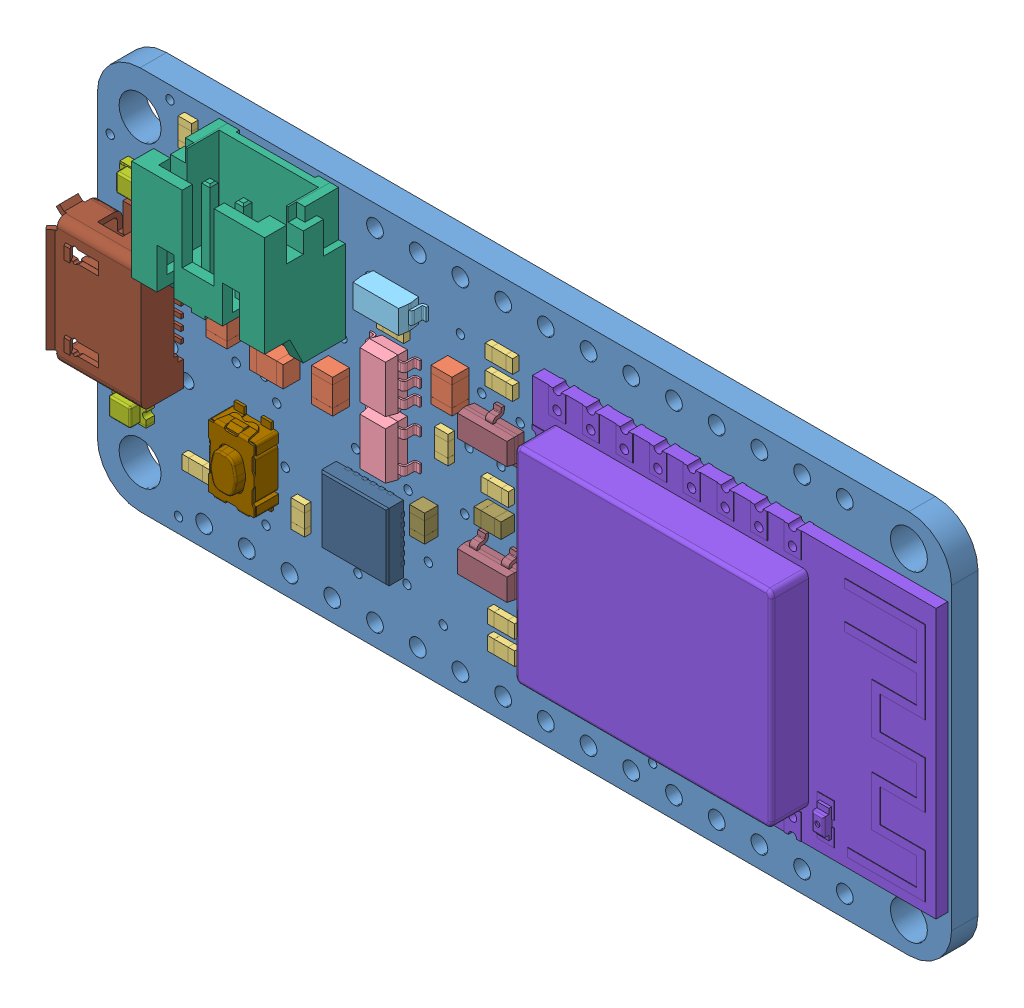
SolidWorks assembly 2821 Adafruit ESP8266 Feather, configuration Default. Lengths in mm.
Overall size (51.25 22.86 6.37).
31 component instances, 13 part files, 0 mates.
Components (placement in the parent):
- 2821 Adafruit ESP8266 Feather(2)^2821 Adafruit ESP8266 Feather-1: 2821 Adafruit ESP8266 Feather(2)^2821 Adafruit ESP8266 Feather [Default] at origin size (51.25 22.86 6.37) (virtual)
  - PCB Component^2821 Adafruit ESP8266 Feather(2)_2821 Adafruit ESP8266 Feather-1: PCB Component^2821 Adafruit ESP8266 Feather(2)_2821 Adafruit ESP8266 Feather [Default] at origin size (51.25 22.86 6.37) (virtual)
    - Board^PCB Component_2821 Adafruit ESP8266 Feather(2)_2821 Adafruit ESP8266 Feather-1: Board^PCB Component_2821 Adafruit ESP8266 Feather(2)_2821 Adafruit ESP8266 Feather [Default] at origin size (50.8 22.86 1.57) (virtual)
    - 10uF^PCB Component_2821 Adafruit ESP8266 Feather(2)_2821 Adafruit ESP8266 Feather-1: 10uF^PCB Component_2821 Adafruit ESP8266 Feather(2)_2821 Adafruit ESP8266 Feather [Default] at (8.088 12.959 1.57) x (0 1 0) z (0 0 1) size (2 1.25 1) (virtual)
    - 10uF^PCB Component_2821 Adafruit ESP8266 Feather(2)_2821 Adafruit ESP8266 Feather-2: 10uF^PCB Component_2821 Adafruit ESP8266 Feather(2)_2821 Adafruit ESP8266 Feather [Default] at (14.366 12.64 1.57) x (0 -1 0) z (0 0 1) size (2 1.25 1) (virtual)
    - 10uF^PCB Component_2821 Adafruit ESP8266 Feather(2)_2821 Adafruit ESP8266 Feather-3: 10uF^PCB Component_2821 Adafruit ESP8266 Feather(2)_2821 Adafruit ESP8266 Feather [Default] at (11.049 12.192 1.57) x (-1 0 0) z (0 0 1) size (2 1.25 1) (virtual)
    - 10uF^PCB Component_2821 Adafruit ESP8266 Feather(2)_2821 Adafruit ESP8266 Feather-4: 10uF^PCB Component_2821 Adafruit ESP8266 Feather(2)_2821 Adafruit ESP8266 Feather [Default] at (21.463 16.192 1.57) x (0 -1 0) z (0 0 1) size (2 1.25 1) (virtual)
    - 10K^PCB Component_2821 Adafruit ESP8266 Feather(2)_2821 Adafruit ESP8266 Feather-1: 10K^PCB Component_2821 Adafruit ESP8266 Feather(2)_2821 Adafruit ESP8266 Feather [Default] at (12.302 4.775 1.57) x (0 -1 0) z (0 0 1) size (1.62 0.81 0.38) (virtual)
    - 10K^PCB Component_2821 Adafruit ESP8266 Feather(2)_2821 Adafruit ESP8266 Feather-2: 10K^PCB Component_2821 Adafruit ESP8266 Feather(2)_2821 Adafruit ESP8266 Feather [Default] at (6.223 4.191 1.57) size (1.62 0.81 0.38) (virtual)
    - 10K^PCB Component_2821 Adafruit ESP8266 Feather(2)_2821 Adafruit ESP8266 Feather-3: 10K^PCB Component_2821 Adafruit ESP8266 Feather(2)_2821 Adafruit ESP8266 Feather [Default] at (20.828 12.7 1.57) x (0 -1 0) z (0 0 1) size (1.62 0.81 0.38) (virtual)
    - 10K^PCB Component_2821 Adafruit ESP8266 Feather(2)_2821 Adafruit ESP8266 Feather-4: 10K^PCB Component_2821 Adafruit ESP8266 Feather(2)_2821 Adafruit ESP8266 Feather [Default] at (24.257 18.923 1.57) x (-1 0 0) z (0 0 1) size (1.62 0.81 0.38) (virtual)
    - 10K^PCB Component_2821 Adafruit ESP8266 Feather(2)_2821 Adafruit ESP8266 Feather-5: 10K^PCB Component_2821 Adafruit ESP8266 Feather(2)_2821 Adafruit ESP8266 Feather [Default] at (24.257 17.526 1.57) x (-1 0 0) z (0 0 1) size (1.62 0.81 0.38) (virtual)
    - 10K^PCB Component_2821 Adafruit ESP8266 Feather(2)_2821 Adafruit ESP8266 Feather-6: 10K^PCB Component_2821 Adafruit ESP8266 Feather(2)_2821 Adafruit ESP8266 Feather [Default] at (24.384 3.937 1.57) size (1.62 0.81 0.38) (virtual)
    - 10K^PCB Component_2821 Adafruit ESP8266 Feather(2)_2821 Adafruit ESP8266 Feather-7: 10K^PCB Component_2821 Adafruit ESP8266 Feather(2)_2821 Adafruit ESP8266 Feather [Default] at (24.384 5.334 1.57) x (-1 0 0) z (0 0 1) size (1.62 0.81 0.38) (virtual)
    - 10K^PCB Component_2821 Adafruit ESP8266 Feather(2)_2821 Adafruit ESP8266 Feather-8: 10K^PCB Component_2821 Adafruit ESP8266 Feather(2)_2821 Adafruit ESP8266 Feather [Default] at (5.588 21.082 1.57) x (0 -1 0) z (0 0 1) size (1.62 0.81 0.38) (virtual)
    - 10K^PCB Component_2821 Adafruit ESP8266 Feather(2)_2821 Adafruit ESP8266 Feather-9: 10K^PCB Component_2821 Adafruit ESP8266 Feather(2)_2821 Adafruit ESP8266 Feather [Default] at (24.003 11.938 1.57) x (-1 0 0) z (0 0 1) size (1.62 0.81 0.38) (virtual)
    - 10K^PCB Component_2821 Adafruit ESP8266 Feather(2)_2821 Adafruit ESP8266 Feather-10: 10K^PCB Component_2821 Adafruit ESP8266 Feather(2)_2821 Adafruit ESP8266 Feather [Default] at (17.78 17.272 1.57) size (1.62 0.81 0.38) (virtual)
    - MCP73831T-2ACI_OT^PCB Component_2821 Adafruit ESP8266 Feather(2)_2821 Adafruit ESP8266 Feather-1: MCP73831T-2ACI_OT^PCB Component_2821 Adafruit ESP8266 Feather(2)_2821 Adafruit ESP8266 Feather [Default] at (17.78 14.986 1.57) x (0 1 0) z (0 0 1) size (3 3 1.4) (virtual)
    - MCP73831T-2ACI_OT^PCB Component_2821 Adafruit ESP8266 Feather(2)_2821 Adafruit ESP8266 Feather-2: MCP73831T-2ACI_OT^PCB Component_2821 Adafruit ESP8266 Feather(2)_2821 Adafruit ESP8266 Feather [Default] at (17.78 11.557 1.57) x (0 -1 0) z (0 0 1) size (3 3 1.4) (virtual)
    - MBR120^PCB Component_2821 Adafruit ESP8266 Feather(2)_2821 Adafruit ESP8266 Feather-1: MBR120^PCB Component_2821 Adafruit ESP8266 Feather(2)_2821 Adafruit ESP8266 Feather [Default] at (17.907 18.796 1.57) x (-1 0 0) z (0 0 1) size (3.6 1.4 1.35) (virtual)
    - JSTPH^PCB Component_2821 Adafruit ESP8266 Feather(2)_2821 Adafruit ESP8266 Feather-1: JSTPH^PCB Component_2821 Adafruit ESP8266 Feather(2)_2821 Adafruit ESP8266 Feather [Default] at (10.795 19.304 1.57) size (7.9 8.6 4.8) (virtual)
    - RED^PCB Component_2821 Adafruit ESP8266 Feather(2)_2821 Adafruit ESP8266 Feather-1: RED^PCB Component_2821 Adafruit ESP8266 Feather(2)_2821 Adafruit ESP8266 Feather [Default] at (2.413 5.588 1.57) x (0 -1 0) z (0 0 1) size (1.25 2.02 1.1) (virtual)
    - RED^PCB Component_2821 Adafruit ESP8266 Feather(2)_2821 Adafruit ESP8266 Feather-2: RED^PCB Component_2821 Adafruit ESP8266 Feather(2)_2821 Adafruit ESP8266 Feather [Default] at (2.858 17.336 1.57) x (0 -1 0) z (0 0 1) size (1.25 2.02 1.1) (virtual)
    - ESP-12^PCB Component_2821 Adafruit ESP8266 Feather(2)_2821 Adafruit ESP8266 Feather-1: ESP-12^PCB Component_2821 Adafruit ESP8266 Feather(2)_2821 Adafruit ESP8266 Feather [Default] at (36.322 11.43 1.57) x (0 -1 0) z (0 0 1) size (16 24 2.95) (virtual)
    - KMR2^PCB Component_2821 Adafruit ESP8266 Feather(2)_2821 Adafruit ESP8266 Feather-1: KMR2^PCB Component_2821 Adafruit ESP8266 Feather(2)_2821 Adafruit ESP8266 Feather [Default] at (9.398 6.35 1.57) x (0 -1 0) z (0 0 1) size (4.6 2.8 1.94) (virtual)
    - CP2104^PCB Component_2821 Adafruit ESP8266 Feather(2)_2821 Adafruit ESP8266 Feather-1: CP2104^PCB Component_2821 Adafruit ESP8266 Feather(2)_2821 Adafruit ESP8266 Feather [Default] at (16.256 6.477 1.57) size (4 4 1) (virtual)
    - 20329^PCB Component_2821 Adafruit ESP8266 Feather(2)_2821 Adafruit ESP8266 Feather-1: 20329^PCB Component_2821 Adafruit ESP8266 Feather(2)_2821 Adafruit ESP8266 Feather [Default] at (4.445 11.43 1.57) x (0 -1 0) z (0 0 1) size (8.8 5.6 3) (virtual)
    - 1K^PCB Component_2821 Adafruit ESP8266 Feather(2)_2821 Adafruit ESP8266 Feather-1: 1K^PCB Component_2821 Adafruit ESP8266 Feather(2)_2821 Adafruit ESP8266 Feather [Default] at (24.003 10.541 1.57) size (1.6 0.9 0.8) (virtual)
    - 1K^PCB Component_2821 Adafruit ESP8266 Feather(2)_2821 Adafruit ESP8266 Feather-2: 1K^PCB Component_2821 Adafruit ESP8266 Feather(2)_2821 Adafruit ESP8266 Feather [Default] at (19.812 8.382 1.57) x (0 -1 0) z (0 0 1) size (1.6 0.9 0.8) (virtual)
    - mmbt2222^PCB Component_2821 Adafruit ESP8266 Feather(2)_2821 Adafruit ESP8266 Feather-1: mmbt2222^PCB Component_2821 Adafruit ESP8266 Feather(2)_2821 Adafruit ESP8266 Feather [Default] at (24.003 8.001 1.57) x (-1 0 0) z (0 0 1) size (3.04 2.64 1.12) (virtual)
    - mmbt2222^PCB Component_2821 Adafruit ESP8266 Feather(2)_2821 Adafruit ESP8266 Feather-2: mmbt2222^PCB Component_2821 Adafruit ESP8266 Feather(2)_2821 Adafruit ESP8266 Feather [Default] at (24.003 14.986 1.57) size (3.04 2.64 1.12) (virtual)
